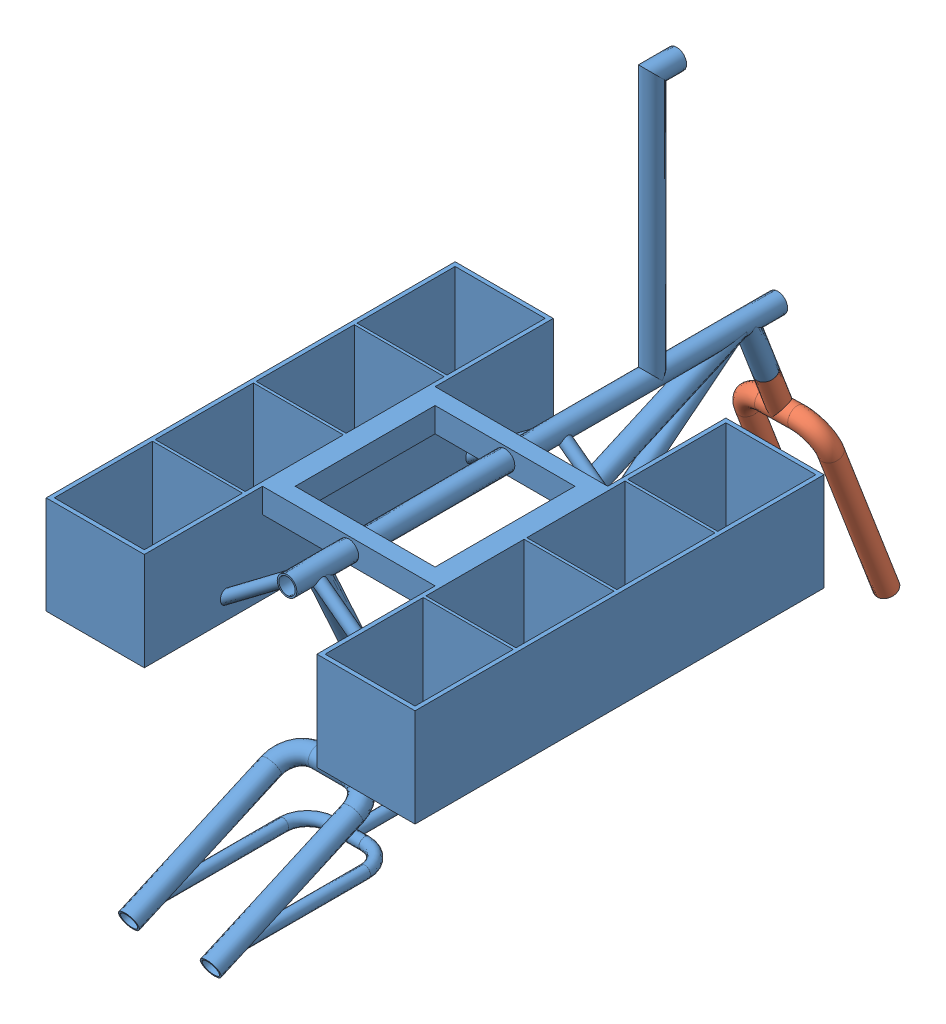
SolidWorks assembly Assem frame, configuration Default. Lengths in mm.
Overall size (796.53 2068.07 2311.96).
2 component instances, 2 part files, 1 mates.
Components (placement in the parent):
- main frame-1: main frame [Default] at origin size (796.53 1611.76 1100)
- frontWheel_fork-1: frontWheel_fork [Default] at (-3.7064 190.2737 -498.0712) x (0.012987 -0.666706 0.745208) z (-0.999903 -0.004961 0.012987) size (1277.02 1589.76 124)
Mates (geometry in assembly coordinates):
- Coincident1: coincident anti-aligned: circle of main frame-1; circle of frontWheel_fork-1
